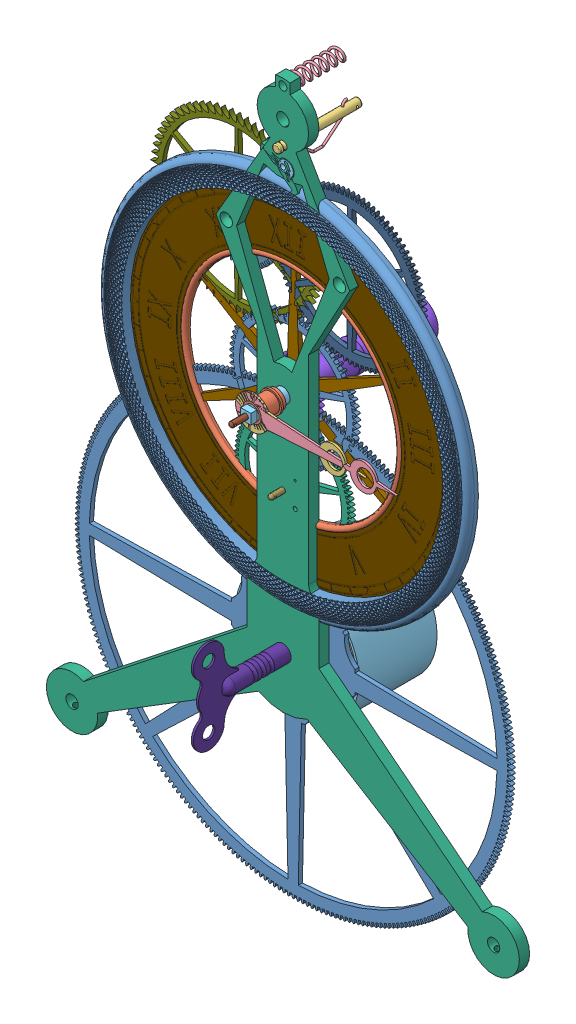
SolidWorks assembly layout, configuration Default. Lengths in mm.
Overall size (219.89 346.85 70.5).
43 component instances, 43 part files, 164 mates.
Components (placement in the parent):
- layout-1: layout [Default] at origin size (219.89 346.85 70.5)
- great wheel-1: great wheel [Default] at origin size (211.89 211.9 2) (hidden)
- great pinion-1: great pinion [Default] at origin size (8.11 8.11 10) (hidden)
- barrel rear cap-1: barrel rear cap [Default] at origin size (57.6 57.6 4) (hidden)
- barrel front cap-1: barrel front cap [Default] at origin size (57.64 57.6 4.06) (hidden)
- barrel-1: barrel [Default] at origin size (60 60 37.9) (hidden)
- Frame-1: Frame [Default] at origin size (229.79 326.05 5) (hidden)
- barrel arbor-1: barrel arbor [Default] at origin size (12 13 98.5) (hidden)
- pillar-1: pillar [Default] at origin size (20 20 70.93) (hidden)
- center wheel-1: center wheel [Default] at origin size (126.9 126.9 2) (hidden)
- third wheel-1: third wheel [Default] at origin size (71.86 71.91 2) (hidden)
- center arbor-1: center arbor [Default] at origin size (4 4 96.9) (hidden)
- center collet-1: center collet [Default] at origin size (18 18 16) (hidden)
- washer-1: washer [Default] at origin size (20 20 2) (hidden)
- escape drive wheel-1: escape drive wheel [Default] at origin size (41.81 41.89 2) (hidden)
- escape spacer-1: escape spacer [Default] at origin size (12 12 2) (hidden)
- escape wheel-1: escape wheel [Default] at origin size (83.42 83.5 2)
- top arbor-1: top arbor [Default] at origin size (4 4 71.9) (hidden)
- escape collet-1: escape collet [Default] at origin size (12 12 19)
- hour wheel-1: hour wheel [Default] at origin size (61.84 61.91 2)
- motionwork hour pipe-1: motionwork hour pipe [Default] at origin size (10.5 10.5 12) (hidden)
- motionwork hour hand-1: motionwork hour hand [Default] at origin size (63 16 1) (hidden)
- motionwork minute hand-1: motionwork minute hand [Default] at origin size (78 16 1) (hidden)
- motionwork minute pipe-1: motionwork minute pipe [Default] at origin size (7 7 18) (hidden)
- motionwork reduction wheel-1: motionwork reduction wheel [Default] at origin size (56.89 56.89 2) (hidden)
- motionwork reduction pinion-1: motionwork reduction pinion [Default] at origin size (21.83 21.79 5.5) (hidden)
- motionwork minute pinion-1: motionwork minute pinion [Default] at origin size (26.73 26.88 2) (hidden)
- motionwork minute hand support-1: motionwork minute hand support [Default] at origin size (12 12 3) (hidden)
- motionwork endcap-1: motionwork endcap [Default] at origin size (12 12 4) (hidden)
- motionwork taper pin-1: motionwork taper pin [Default] at origin size (7 0.99 0.99) (hidden)
- motionwork reduction pivot-1: motionwork reduction pivot [Default] at origin size (3 3 16.7) (hidden)
- barrel rachet wheel-1: barrel rachet wheel [Default] at origin size (38.92 39 3) (hidden)
- barrel click-1: barrel click [Default] at origin size (17.17 29.82 2) (hidden)
- barrel assy shoulder bolt-1: barrel assy shoulder bolt [Default] at origin size (8.5 8.5 10.5) (hidden)
- barrel click spring-1: barrel click spring [Default] at origin size (8.83 43.99 1.56) (hidden)
- winding key-1: winding key [Default] at origin size (8 45 49) (hidden)
- chapter ring-1: chapter ring [Default] at origin size (160 160 1) (hidden)
- chapter ring outer bezel-2: chapter ring outer bezel [Default] at origin size (180 180 5.64) (hidden)
- chapter ring inner bezel-1: chapter ring inner bezel [Default] at origin size (108 108 2.5) (hidden)
- suspension post-1: suspension post [Default] at (-27.8586 4.1717 3.2925) size (4 4 40) (hidden)
- suspension rope-1: suspension rope [Default] at origin size (8.06 39.53 26.5) (hidden)
- eccentric bushing-1: eccentric bushing [Default] at origin size (10.4 10.4 7) (hidden)
- escape pallets-1: escape pallets [Default] at origin size (18.3 15.59 5)
Mates (geometry in assembly coordinates):
- InPlace1: in place: plane of ? through (0 0 0) normal (0 0 1); moOrthogonalPlaneRef_w of ? through (0 0 0) normal (0 1 0); plane of ? through (0 0 0) normal (1 0 0); unknown of ?
- Coincident1: coincident: plane of great wheel-1; plane of assembly
- Coincident2: coincident: plane of ? through (0 0 0) normal (0 1 0)
- Coincident3: coincident: plane of ? through (0 0 0) normal (1 0 0)
- InPlace2: in place: plane of ? through (0 0 0) normal (0 0 1); plane of ? through (0 0 0) normal (0 1 0); plane of ? through (0 0 0) normal (1 0 0); unknown of ?
- Coincident4: coincident: plane of great pinion-1; plane of assembly
- Coincident5: coincident: plane of ? through (0 0 0) normal (0 1 0)
- Coincident6: coincident: plane of ? through (0 0 0) normal (1 0 0)
- InPlace3: in place: plane of ? through (0 0 0) normal (0 0 1); plane of ? through (0 0 0) normal (0 1 0); plane of ? through (0 0 0) normal (1 0 0); unknown of ?
- Coincident1: coincident: plane of barrel rear cap-1; plane of assembly
- Coincident2: coincident: plane of ? through (0 0 0) normal (0 1 0)
- Coincident3: coincident: plane of ? through (0 0 0) normal (1 0 0)
- InPlace4: in place: plane of ? through (0 0 0) normal (0 0 1); plane of ? through (0 0 0) normal (0 1 0); plane of ? through (0 0 0) normal (1 0 0); unknown of ?
- Coincident4: coincident: plane of barrel front cap-1; plane of assembly
- Coincident5: coincident: plane of ? through (0 0 0) normal (0 1 0)
- Coincident6: coincident: plane of ? through (0 0 0) normal (1 0 0)
- InPlace5: in place: plane of ? through (0 0 0) normal (0 0 1); plane of ? through (0 0 0) normal (0 1 0); plane of ? through (0 0 0) normal (1 0 0); unknown of ?
- Coincident7: coincident: plane of barrel-1; plane of assembly
- Coincident8: coincident: plane of ? through (0 0 0) normal (0 1 0)
- Coincident9: coincident: plane of ? through (0 0 0) normal (1 0 0)
- InPlace6: in place: plane of ? through (0 0 0) normal (0 0 1); plane of ? through (0 0 0) normal (0 1 0); plane of ? through (0 0 0) normal (1 0 0); unknown of ?
- Coincident10: coincident: plane of Frame-1; plane of assembly
- Coincident11: coincident: plane of ? through (0 0 0) normal (0 1 0)
- Coincident12: coincident: plane of ? through (0 0 0) normal (1 0 0)
- InPlace7: in place: plane of ? through (0 0 0) normal (0 0 1); plane of ? through (0 0 0) normal (0 1 0); plane of ? through (0 0 0) normal (1 0 0); unknown of ?
- Coincident13: coincident: plane of barrel arbor-1; plane of assembly
- Coincident14: coincident: plane of ? through (0 0 0) normal (0 1 0)
- Coincident15: coincident: plane of ? through (0 0 0) normal (1 0 0)
- InPlace8: in place: plane of ? through (0 0 0) normal (0 0 1); plane of ? through (0 0 0) normal (0 1 0); plane of ? through (0 0 0) normal (1 0 0); unknown of ?
- Coincident16: coincident: plane of pillar-1; plane of assembly
- Coincident17: coincident: plane of ? through (0 0 0) normal (0 1 0)
- Coincident18: coincident: plane of ? through (0 0 0) normal (1 0 0)
- InPlace9: in place: plane of ? through (0 0 0) normal (0 0 1); plane of ? through (0 0 0) normal (0 1 0); plane of ? through (0 0 0) normal (1 0 0); unknown of ?
- Coincident1: coincident: plane of center wheel-1; plane of assembly
- Coincident2: coincident: plane of ? through (0 0 0) normal (0 1 0)
- Coincident3: coincident: plane of ? through (0 0 0) normal (1 0 0)
- InPlace10: in place: plane of ? through (0 0 0) normal (0 0 1); plane of ? through (0 0 0) normal (0 1 0); plane of ? through (0 0 0) normal (1 0 0); unknown of ?
- Coincident4: coincident: plane of third wheel-1; plane of assembly
- Coincident5: coincident: plane of ? through (0 0 0) normal (0 1 0)
- Coincident6: coincident: plane of ? through (0 0 0) normal (1 0 0)
- InPlace11: in place: plane of ? through (0 0 0) normal (0 0 1); plane of ? through (0 0 0) normal (0 0 1); plane of ? through (0 0 0) normal (0 0 1); plane of ? through (0 0 0) normal (0 1 0); plane of ? through (0 0 0) normal (0 0 1); plane of ? through (0 0 0) normal (1 0 0); plane of ? through (0 0 0) normal (0 0 1); unknown of ?
- Coincident7: coincident: plane of layout-1; plane of center arbor-1
- Coincident8: coincident: moOrthogonalPlaneRef_w of layout-1 through (-181.596 0 0) axis (0 0 1); plane of center arbor-1 through (0 0 0) normal (0 1 0)
- Coincident9: coincident: moOrthogonalPlaneRef_w of layout-1 through (181.596 -181.596 0) axis (0 0 -1); plane of center arbor-1 through (0 0 0) normal (1 0 0)
- InPlace12: in place: plane of ? through (0 0 0) normal (0 0 1); plane of ? through (0 0 0) normal (0 1 0); plane of ? through (0 0 0) normal (1 0 0); unknown of ?
- Coincident10: coincident: plane of center collet-1; plane of assembly
- Coincident11: coincident: plane of ? through (0 0 0) normal (0 1 0)
- Coincident12: coincident: plane of ? through (0 0 0) normal (1 0 0)
- InPlace13: in place: plane of ? through (0 0 0) normal (0 0 1); plane of ? through (0 0 0) normal (0 0 1); plane of ? through (0 0 0) normal (0 0 1); plane of ? through (0 0 0) normal (0 1 0); plane of ? through (0 0 0) normal (0 0 1); plane of ? through (0 0 0) normal (1 0 0); plane of ? through (0 0 0) normal (0 0 1); unknown of ?
- Coincident13: coincident: plane of layout-1; plane of washer-1
- Coincident14: coincident: moOrthogonalPlaneRef_w of layout-1 through (-112.8584 0 0) axis (0 0 1); plane of washer-1 through (0 0 0) normal (0 1 0)
- Coincident15: coincident: moOrthogonalPlaneRef_w of layout-1 through (112.8584 -112.8584 0) axis (0 0 -1); plane of washer-1 through (0 0 0) normal (1 0 0)
- InPlace14: in place: plane of ? through (0 0 0) normal (0 0 1); plane of ? through (0 0 0) normal (0 0 1); plane of ? through (0 0 0) normal (0 0 1); plane of ? through (0 0 0) normal (0 1 0); plane of ? through (0 0 0) normal (0 0 1); plane of ? through (0 0 0) normal (1 0 0); plane of ? through (0 0 0) normal (0 0 1); unknown of ?
- Coincident16: coincident: plane of layout-1; plane of escape drive wheel-1
- Coincident17: coincident: moOrthogonalPlaneRef_w of layout-1 through (-179.7057 0 0) axis (0 0 1); plane of escape drive wheel-1 through (0 0 0) normal (0 1 0)
- Coincident18: coincident: moOrthogonalPlaneRef_w of layout-1 through (179.7057 -179.7057 0) axis (0 0 -1); plane of escape drive wheel-1 through (0 0 0) normal (1 0 0)
- InPlace15: in place: plane of ? through (0 0 0) normal (0 0 1); plane of ? through (0 0 0) normal (0 1 0); plane of ? through (0 0 0) normal (1 0 0); unknown of ?
- Coincident19: coincident: plane of escape spacer-1; plane of assembly
- Coincident20: coincident: plane of ? through (0 0 0) normal (0 1 0)
- Coincident21: coincident: plane of ? through (0 0 0) normal (1 0 0)
- InPlace16: in place: plane of ? through (0 0 0) normal (0 0 1); plane of ? through (0 0 0) normal (0 1 0); plane of ? through (0 0 0) normal (1 0 0); unknown of ?
- Coincident22: coincident: plane of escape wheel-1; plane of assembly
- Coincident23: coincident: plane of ? through (0 0 0) normal (0 1 0)
- Coincident24: coincident: plane of ? through (0 0 0) normal (1 0 0)
- InPlace17: in place: plane of ? through (0 0 0) normal (0 0 1); plane of ? through (0 0 0) normal (0 1 0); plane of ? through (0 0 0) normal (1 0 0); unknown of ?
- Coincident25: coincident: plane of top arbor-1; plane of assembly
- Coincident26: coincident: plane of ? through (0 0 0) normal (0 1 0)
- Coincident27: coincident: plane of ? through (0 0 0) normal (1 0 0)
- InPlace18: in place: plane of ? through (0 0 0) normal (0 0 1); plane of ? through (0 0 0) normal (0 1 0); plane of ? through (0 0 0) normal (1 0 0); unknown of ?
- Coincident28: coincident: plane of escape collet-1; plane of assembly
- Coincident29: coincident: plane of ? through (0 0 0) normal (0 1 0)
- Coincident30: coincident: plane of ? through (0 0 0) normal (1 0 0)
- InPlace19: in place: plane of ? through (0 0 0) normal (0 0 1); plane of ? through (0 0 0) normal (0 1 0); plane of ? through (0 0 0) normal (1 0 0); unknown of ?
- Coincident1: coincident: plane of hour wheel-1; plane of assembly
- Coincident2: coincident: plane of ? through (0 0 0) normal (0 1 0)
- Coincident3: coincident: plane of ? through (0 0 0) normal (1 0 0)
- InPlace20: in place: plane of ? through (0 0 0) normal (0 0 1); plane of ? through (0 0 0) normal (0 1 0); plane of ? through (0 0 0) normal (1 0 0); unknown of ?
- Coincident4: coincident: plane of motionwork hour pipe-1; plane of assembly
- Coincident5: coincident: plane of ? through (0 0 0) normal (0 1 0)
- Coincident6: coincident: plane of ? through (0 0 0) normal (1 0 0)
- InPlace21: in place: plane of ? through (0 0 0) normal (0 0 1); plane of ? through (0 0 0) normal (0 1 0); plane of ? through (0 0 0) normal (1 0 0); unknown of ?
- Coincident7: coincident: plane of motionwork hour hand-1; plane of assembly
- Coincident8: coincident: plane of ? through (0 0 0) normal (0 1 0)
- Coincident9: coincident: plane of ? through (0 0 0) normal (1 0 0)
- InPlace22: in place: plane of ? through (0 0 0) normal (0 0 1); plane of ? through (0 0 0) normal (0 1 0); plane of ? through (0 0 0) normal (1 0 0); unknown of ?
- Coincident10: coincident: plane of motionwork minute hand-1; plane of assembly
- Coincident11: coincident: plane of ? through (0 0 0) normal (0 1 0)
- Coincident12: coincident: plane of ? through (0 0 0) normal (1 0 0)
- InPlace23: in place: plane of ? through (0 0 0) normal (0 0 1); plane of ? through (0 0 0) normal (0 1 0); plane of ? through (0 0 0) normal (1 0 0); unknown of ?
- Coincident13: coincident: plane of motionwork minute pipe-1; plane of assembly
- Coincident14: coincident: plane of ? through (0 0 0) normal (0 1 0)
- Coincident15: coincident: plane of ? through (0 0 0) normal (1 0 0)
- InPlace24: in place: plane of ? through (0 0 0) normal (0 0 1); plane of ? through (0 0 0) normal (0 1 0); plane of ? through (0 0 0) normal (1 0 0); unknown of ?
- Coincident16: coincident: plane of motionwork reduction wheel-1; plane of assembly
- Coincident17: coincident: plane of ? through (0 0 0) normal (0 1 0)
- Coincident18: coincident: plane of ? through (0 0 0) normal (1 0 0)
- InPlace25: in place: plane of ? through (0 0 0) normal (0 0 1); plane of ? through (0 0 0) normal (0 1 0); plane of ? through (0 0 0) normal (1 0 0); unknown of ?
- Coincident19: coincident: plane of motionwork reduction pinion-1; plane of assembly
- Coincident20: coincident: plane of ? through (0 0 0) normal (0 1 0)
- Coincident21: coincident: plane of ? through (0 0 0) normal (1 0 0)
- InPlace26: in place: plane of ? through (0 0 0) normal (0 0 1); plane of ? through (0 0 0) normal (0 1 0); plane of ? through (0 0 0) normal (1 0 0); unknown of ?
- Coincident22: coincident: plane of motionwork minute pinion-1; plane of assembly
- Coincident23: coincident: plane of ? through (0 0 0) normal (0 1 0)
- Coincident24: coincident: plane of ? through (0 0 0) normal (1 0 0)
- InPlace27: in place: plane of ? through (0 0 0) normal (0 0 1); plane of ? through (0 0 0) normal (0 1 0); plane of ? through (0 0 0) normal (1 0 0); unknown of ?
- Coincident1: coincident: plane of motionwork minute hand support-1; plane of assembly
- Coincident2: coincident: plane of ? through (0 0 0) normal (0 1 0)
- Coincident3: coincident: plane of ? through (0 0 0) normal (1 0 0)
- InPlace28: in place: plane of ? through (0 0 0) normal (0 0 1); plane of ? through (0 0 0) normal (0 1 0); plane of ? through (0 0 0) normal (1 0 0); unknown of ?
- Coincident4: coincident: plane of motionwork endcap-1; plane of assembly
- Coincident5: coincident: plane of ? through (0 0 0) normal (0 1 0)
- Coincident6: coincident: plane of ? through (0 0 0) normal (1 0 0)
- InPlace29: in place: plane of ? through (0 0 0) normal (0 0 1); plane of ? through (0 0 0) normal (0 1 0); plane of ? through (0 0 0) normal (1 0 0); unknown of ?
- Coincident7: coincident: plane of motionwork taper pin-1; plane of assembly
- Coincident8: coincident: plane of ? through (0 0 0) normal (0 1 0)
- Coincident9: coincident: plane of ? through (0 0 0) normal (1 0 0)
- InPlace30: in place: plane of ? through (0 0 0) normal (0 0 1); plane of ? through (0 0 0) normal (0 1 0); plane of ? through (0 0 0) normal (1 0 0); unknown of ?
- Coincident10: coincident: plane of motionwork reduction pivot-1; plane of assembly
- Coincident11: coincident: plane of ? through (0 0 0) normal (0 1 0)
- Coincident12: coincident: plane of ? through (0 0 0) normal (1 0 0)
- InPlace31: in place: plane of ? through (0 0 0) normal (0 0 1); plane of ? through (0 0 0) normal (0 1 0); plane of ? through (0 0 0) normal (1 0 0); unknown of ?
- Coincident13: coincident: plane of barrel rachet wheel-1; plane of assembly
- Coincident14: coincident: plane of ? through (0 0 0) normal (0 1 0)
- Coincident15: coincident: plane of ? through (0 0 0) normal (1 0 0)
- InPlace32: in place: plane of ? through (0 0 0) normal (0 0 1); plane of ? through (0 0 0) normal (0 1 0); plane of ? through (0 0 0) normal (1 0 0); unknown of ?
- Coincident16: coincident: plane of barrel click-1; plane of assembly
- Coincident17: coincident: plane of ? through (0 0 0) normal (0 1 0)
- Coincident18: coincident: plane of ? through (0 0 0) normal (1 0 0)
- InPlace33: in place: plane of ? through (0 0 0) normal (0 0 1); plane of ? through (0 0 0) normal (0 1 0); plane of ? through (0 0 0) normal (1 0 0); unknown of ?
- Coincident19: coincident: plane of barrel assy shoulder bolt-1; plane of assembly
- Coincident20: coincident: plane of ? through (0 0 0) normal (0 1 0)
- Coincident21: coincident: plane of ? through (0 0 0) normal (1 0 0)
- InPlace34: in place: plane of ? through (0 0 0) normal (0 0 1); plane of ? through (0 0 0) normal (0 1 0); plane of ? through (0 0 0) normal (1 0 0); unknown of ?
- Coincident22: coincident: plane of barrel click spring-1; plane of assembly
- Coincident23: coincident: plane of ? through (0 0 0) normal (0 1 0)
- Coincident24: coincident: plane of ? through (0 0 0) normal (1 0 0)
- InPlace35: in place: plane of ? through (0 0 0) normal (0 0 1); plane of ? through (0 0 0) normal (0 1 0); plane of ? through (0 0 0) normal (1 0 0); unknown of ?
- Coincident25: coincident: plane of winding key-1; plane of assembly
- Coincident26: coincident: plane of ? through (0 0 0) normal (0 1 0)
- Coincident27: coincident: plane of ? through (0 0 0) normal (1 0 0)
- InPlace36: in place: plane of ? through (0 0 0) normal (0 0 1); plane of ? through (0 0 0) normal (0 1 0); plane of ? through (0 0 0) normal (1 0 0); unknown of ?
- Coincident28: coincident: plane of chapter ring-1; plane of assembly
- Coincident29: coincident: plane of ? through (0 0 0) normal (0 1 0)
- Coincident30: coincident: plane of ? through (0 0 0) normal (1 0 0)
- InPlace38: in place: plane of ? through (0 0 0) normal (0 0 1); plane of ? through (0 0 0) normal (0 1 0); plane of ? through (0 0 0) normal (1 0 0); unknown of ?
- Coincident1: coincident: plane of chapter ring outer bezel-2; plane of assembly
- Coincident2: coincident: plane of ? through (0 0 0) normal (0 1 0)
- Coincident3: coincident: plane of ? through (0 0 0) normal (1 0 0)
- InPlace39: in place: plane of ? through (0 0 0) normal (0 0 1); plane of ? through (0 0 0) normal (0 1 0); plane of ? through (0 0 0) normal (1 0 0); unknown of ?
- Coincident4: coincident: plane of chapter ring inner bezel-1; plane of assembly
- Coincident5: coincident: plane of ? through (0 0 0) normal (0 1 0)
- Coincident6: coincident: plane of ? through (0 0 0) normal (1 0 0)
- InPlace40: in place: plane of ? through (0 0 0) normal (0 0 1); plane of ? through (0 0 0) normal (0 1 0); plane of ? through (0 0 0) normal (1 0 0); unknown of ?
- Coincident1: coincident: plane of suspension rope-1; plane of assembly
- Coincident2: coincident: plane of ? through (0 0 0) normal (0 1 0)
- Coincident3: coincident: plane of ? through (0 0 0) normal (1 0 0)
- InPlace41: in place: plane of ? through (0 0 0) normal (0 0 1); plane of ? through (0 0 0) normal (0 1 0); plane of ? through (0 0 0) normal (1 0 0); unknown of ?
- Coincident1: coincident: plane of eccentric bushing-1; plane of assembly
- Coincident2: coincident: plane of ? through (0 0 0) normal (0 1 0)
- Coincident3: coincident: plane of ? through (0 0 0) normal (1 0 0)
- InPlace42: in place: plane of ? through (0 0 0) normal (0 0 1); plane of ? through (0 0 0) normal (0 1 0); plane of ? through (0 0 0) normal (1 0 0); unknown of ?
- Coincident4: coincident: plane of escape pallets-1; plane of assembly
- Coincident5: coincident: plane of ? through (0 0 0) normal (0 1 0)
- Coincident6: coincident: plane of ? through (0 0 0) normal (1 0 0)
